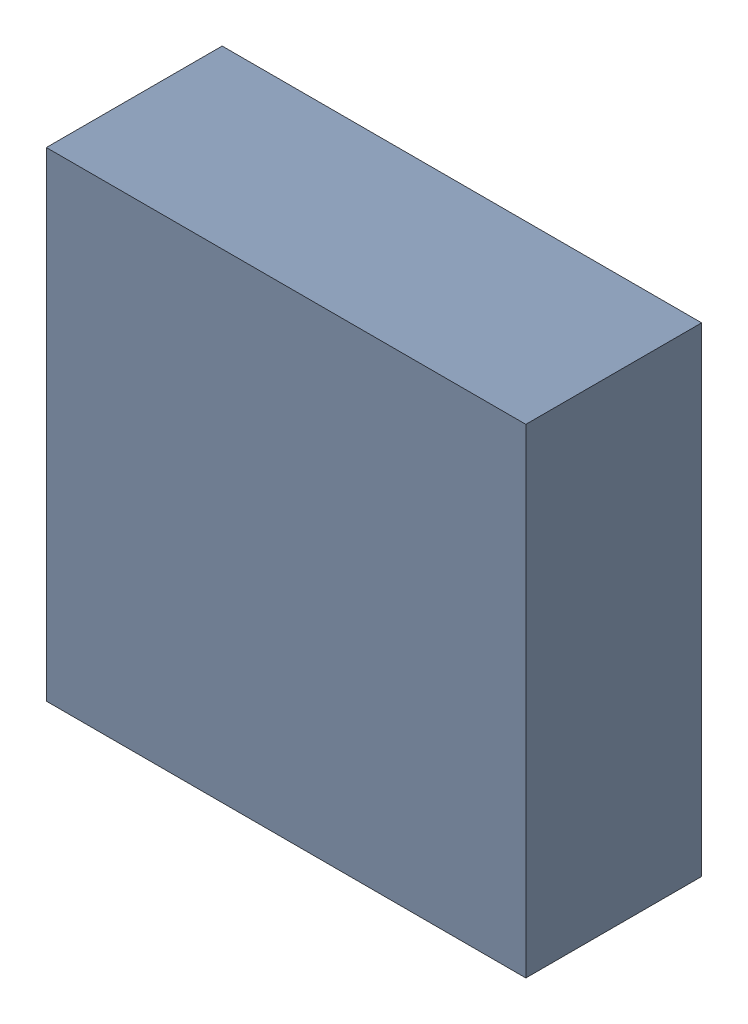
SolidWorks assembly U30, configuration ﾃﾞﾌｫﾙﾄ. Lengths in mm.
Overall size (3 3 1.1).
2 component instances, 1 part files, 0 mates.
Components (placement in the parent):
- 689263144-1: 689263144 [ﾃﾞﾌｫﾙﾄ] at (23 26.75 0) size (3 3 1.1)
  - Extruded_45-1: Extruded_45 [ﾃﾞﾌｫﾙﾄ] at origin size (3 3 1.1)
